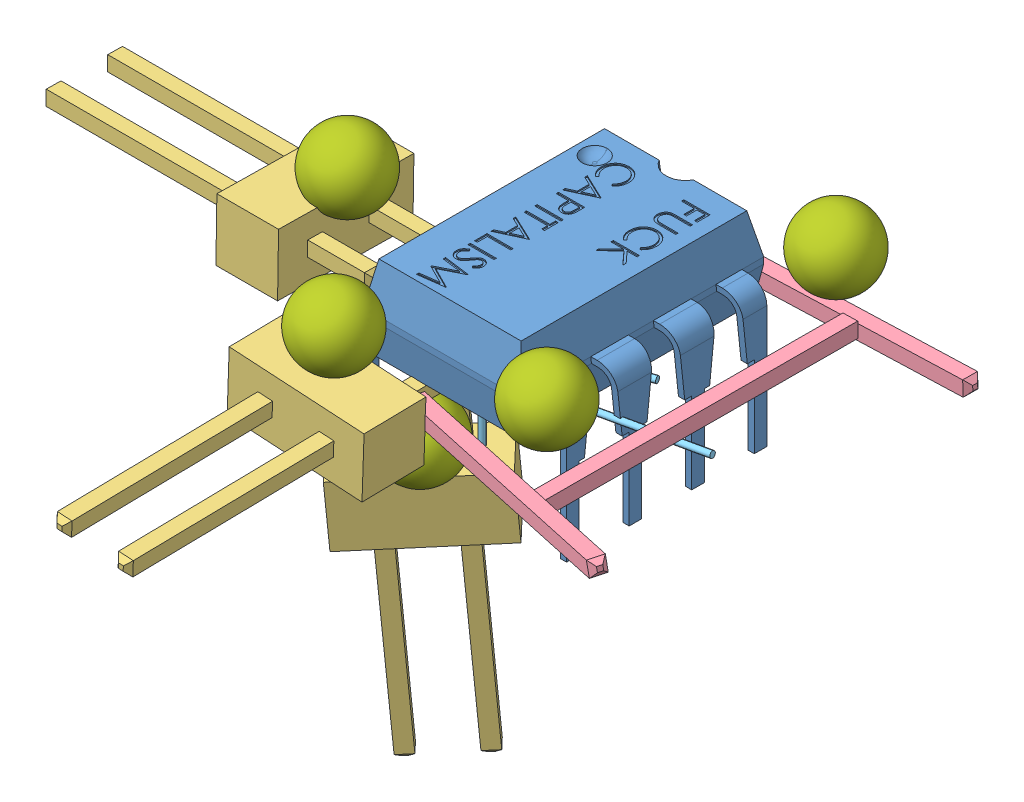
SolidWorks assembly opAmpStone1, configuration Default. Lengths in mm.
Overall size (30.97 19.41 24.4).
25 component instances, 7 part files, 0 mates.
Components (placement in the parent):
- 8-pin-dip-1: 8-pin-dip [Default] at (1.8926 8.8192 6.0767) size (8.38 7.37 9.91)
- 0603resistorapprox-1: 0603resistorapprox [Default] at (2.1534 6.6238 12.2704) size (2 0.56 0.76)
- 0603resistorapprox-2: 0603resistorapprox [Default] at (2.1541 6.6246 9.6312) size (2 0.56 0.76)
- 0603resistorapprox-3: 0603resistorapprox [Default] at (-0.031 6.0648 9.8521) size (2 0.56 0.76)
- 0603resistorapprox-4: 0603resistorapprox [Default] at (1.7102 6.9272 13.7011) x (0.016754 0.018805 -0.999683) z (-0.012455 0.999749 0.018598) size (2 0.56 0.76)
- samtec2pin-1: samtec2pin [Default] at (-6.0951 6.5066 11.2034) x (-0.001046 -0.015333 -0.999882) z (-0.000563 -0.999882 0.015333) size (5.5 13.3 2.5)
- samtec2pin-2: samtec2pin [Default] at (2.2779 0.4106 13.7935) x (0.72406 0.075783 -0.685561) z (0.688948 -0.031935 0.724107) size (5.5 13.3 2.5)
- samtec2pin-3: samtec2pin [Default] at (2.6754 6.8594 19.506) x (-0.998421 0.056059 -0.003544) z (-0.055965 -0.998177 -0.022611) size (5.5 13.3 2.5)
- samtec1pinonly-1: samtec1pinonly [Default] at (12.7604 7.9672 13.8905) x (0.999766 0.021308 -0.00384) z (0.021337 -0.999744 0.007577) size (0.6 13.3 0.6)
- samtec1pinonly-2: samtec1pinonly [Default] at (12.0719 7.1604 19.1303) x (0.204031 -0.978964 0.000175) z (-0.341856 -0.07108 0.93706) size (0.6 13.3 0.6)
- samtec1pinonly-3: samtec1pinonly [Default] at (7.8893 8.8677 5.4395) x (-0.038839 0.999227 -0.006018) z (-0.004434 0.00585 0.999973) size (0.6 13.3 0.6)
- 5mmStub-1: 5mmStub [Default] at (12.5772 7.2452 12.4868) x (0.111383 -0.046925 0.992669) z (0.083903 -0.994874 -0.056443) size (0.25 5 0.25)
- 5mmStub-2: 5mmStub [Default] at (3.9879 6.9837 5.0745) x (-0.646625 0.756035 -0.101424) z (0.749104 0.65446 0.102593) size (0.25 5 0.25)
- 5mmStub-3: 5mmStub [Default] at (8.0367 6.4533 10.1815) x (-0.143905 0.89112 -0.430345) z (0.273286 0.453746 0.848192) size (0.25 5 0.25)
- 5mmStub-4: 5mmStub [Default] at (3.3613 2.2865 12.6229) size (0.25 5 0.25)
- 5mmStub-5: 5mmStub [Default] at (1.9948 5.9323 12.7978) x (-0.099628 -0.212658 0.972034) z (-0.032669 -0.975669 -0.216801) size (0.25 5 0.25)
- 1mmBallRock-1: 1mmBallRock [Default] at (2.6246 6.703 10.5031) size (1 1 1)
- 1mmBallRock-2: 1mmBallRock [Default] at (4.3036 6.2295 7.868) size (1 1 1)
- 1mmBallRock-3: 1mmBallRock [Default] at (5.7656 6.6256 11.5392) size (1 1 1)
- 1mmBallRock-4: 1mmBallRock [Default] at (2.6497 6.8645 13.229) size (1 1 1)
- 3mmBall-1: 3mmBall [Default] at (9.8307 9.3919 16.4662) size (3 3 3)
- 3mmBall-2: 3mmBall [Default] at (10.0358 9.0687 4.9392) size (3 3 3)
- 3mmBall-3: 3mmBall [Default] at (2.5772 9.044 17.8548) size (3 3 3)
- 3mmBall-4: 3mmBall [Default] at (-3.6997 8.0593 11.0336) size (3 3 3)
- 3mmBall-5: 3mmBall [Default] at (3.262 4.0673 15.0456) size (3 3 3)
